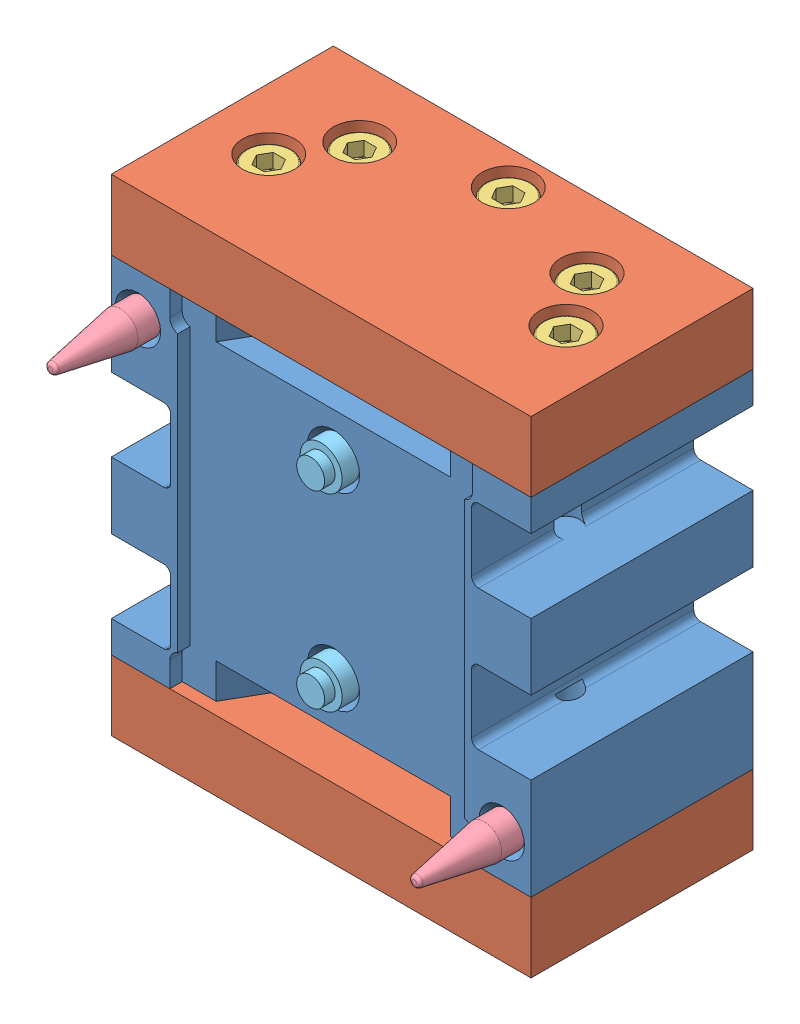
SolidWorks assembly Матрица в сборе, configuration По умолчанию. Lengths in mm.
Overall size (120 139 88.5).
17 component instances, 5 part files, 34 mates.
Components (placement in the parent):
- Матрица-1: Матрица [По умолчанию] at origin size (120 99 63.5)
- Боковина пресс-формы-1: Боковина пресс-формы [По умолчанию] at (0 -49.5 31.75) x (1 0 0) z (0 -1 0) size (120 63.5 20)
- socket head cap screw_iso-1: socket head cap screw_iso [ISO 4762 M8 x 16 - 16N] at (-42.5 -67.5 36) x (0 1 0) z (0 0 1) size (24 13 13)
- socket head cap screw_iso-2: socket head cap screw_iso [ISO 4762 M8 x 16 - 16N] at (-32.5 -67.5 20) x (0 1 0) z (0 0 1) size (24 13 13)
- socket head cap screw_iso-3: socket head cap screw_iso [ISO 4762 M8 x 16 - 16N] at (0 -67.5 10) x (0 1 0) z (0 0 1) size (24 13 13)
- socket head cap screw_iso-4: socket head cap screw_iso [ISO 4762 M8 x 16 - 16N] at (32.5 -67.5 20) x (0 1 0) z (0 0 1) size (24 13 13)
- socket head cap screw_iso-5: socket head cap screw_iso [ISO 4762 M8 x 16 - 16N] at (42.5 -67.5 36) x (0 1 0) z (0 0 1) size (24 13 13)
- socket head cap screw_iso-11: socket head cap screw_iso [ISO 4762 M8 x 16 - 16N] at (-42.5 67.5 36) x (0 -1 0) z (0 0 1) size (24 13 13)
- socket head cap screw_iso-12: socket head cap screw_iso [ISO 4762 M8 x 16 - 16N] at (-32.5 67.5 20) x (0 -1 0) z (0 0 1) size (24 13 13)
- socket head cap screw_iso-13: socket head cap screw_iso [ISO 4762 M8 x 16 - 16N] at (0 67.5 10) x (0 -1 0) z (0 0 1) size (24 13 13)
- socket head cap screw_iso-14: socket head cap screw_iso [ISO 4762 M8 x 16 - 16N] at (32.5 67.5 20) x (0 -1 0) z (0 0 1) size (24 13 13)
- socket head cap screw_iso-15: socket head cap screw_iso [ISO 4762 M8 x 16 - 16N] at (42.5 67.5 36) x (0 -1 0) z (0 0 1) size (24 13 13)
- Боковина пресс-формы-3: Боковина пресс-формы [По умолчанию] at (0 49.5 31.75) x (-1 0 0) z (0 1 0) size (120 63.5 20)
- КОнус-1: КОнус [По умолчанию] at (-52.375 37.5 33.5) x (0 0 1) z (-0.953769 -0.300541 0) size (55 10 10)
- КОнус-2: КОнус [По умолчанию] at (51.625 -37.5 33.5) x (0 0 1) z (-0.599492 0.800381 0) size (55 10 10)
- ВТулка-1: ВТулка [По умолчанию] at (0 27 30) x (0 0 1) z (-0.845392 0.534146 0) size (36.5 12 12)
- ВТулка-2: ВТулка [По умолчанию] at (0 -27 30) x (0 0 1) z (-0.844306 0.535861 0) size (36.5 12 12)
Mates (geometry in assembly coordinates):
- Совпадение1: coincident anti-aligned: plane of Матрица-1 through (-60 -49.5 63.5) normal (0 -1 0); plane of Боковина пресс-формы-1 through (0 -49.5 31.75) normal (0 1 0)
- Концентричный1: concentric aligned: cylinder of Матрица-1 through (42.5 -19.5 36) axis (0 -1 0) radius 4; cylinder of Боковина пресс-формы-1 through (42.5 -49.5 36) axis (0 -1 0) radius 4
- Концентричный2: concentric aligned: cylinder of Матрица-1 through (-42.5 -19.5 36) axis (0 -1 0) radius 4; cylinder of Боковина пресс-формы-1 through (-42.5 -49.5 36) axis (0 -1 0) radius 4
- Концентричный3: concentric aligned: cylinder of Боковина пресс-формы-1 through (-42.5 -49.5 36) axis (0 -1 0) radius 4; cylinder of socket head cap screw_iso-1 through (-42.5 -99.25 36) axis (0 -1 0) radius 6.5
- Совпадение2: coincident anti-aligned: plane of Боковина пресс-формы-1 through (-42.5 -59.5 36) normal (0 -1 0); plane of socket head cap screw_iso-1 through (-49 -59.5 36) normal (0 1 0)
- Концентричный4: concentric aligned: cylinder of Боковина пресс-формы-1 through (-32.5 -49.5 20) axis (0 -1 0) radius 4; cylinder of socket head cap screw_iso-2 through (-32.5 -99.25 20) axis (0 -1 0) radius 6.5
- Совпадение3: coincident anti-aligned: plane of Боковина пресс-формы-1 through (-32.5 -59.5 20) normal (0 -1 0); plane of socket head cap screw_iso-2 through (-39 -59.5 20) normal (0 1 0)
- Концентричный5: concentric aligned: cylinder of Боковина пресс-формы-1 through (0 -59.5 10) axis (0 -1 0) radius 7.5; cylinder of socket head cap screw_iso-3 through (0 -99.25 10) axis (0 -1 0) radius 6.5
- Совпадение4: coincident anti-aligned: plane of Боковина пресс-формы-1 through (0 -59.5 10) normal (0 -1 0); plane of socket head cap screw_iso-3 through (-6.5 -59.5 10) normal (0 1 0)
- Концентричный6: concentric aligned: cylinder of Боковина пресс-формы-1 through (32.5 -59.5 20) axis (0 -1 0) radius 7.5; cylinder of socket head cap screw_iso-4 through (32.5 -99.25 20) axis (0 -1 0) radius 6.5
- Совпадение5: coincident anti-aligned: plane of Боковина пресс-формы-1 through (32.5 -59.5 20) normal (0 -1 0); plane of socket head cap screw_iso-4 through (26 -59.5 20) normal (0 1 0)
- Концентричный7: concentric aligned: cylinder of Боковина пресс-формы-1 through (42.5 -59.5 36) axis (0 -1 0) radius 7.5; cylinder of socket head cap screw_iso-5 through (42.5 -99.25 36) axis (0 -1 0) radius 6.5
- Совпадение6: coincident anti-aligned: plane of Боковина пресс-формы-1 through (42.5 -59.5 36) normal (0 -1 0); plane of socket head cap screw_iso-5 through (36 -59.5 36) normal (0 1 0)
- Совпадение7: coincident anti-aligned: plane of Матрица-1 through (-60 49.5 63.5) normal (0 1 0); plane of Боковина пресс-формы-3 through (0 49.5 31.75) normal (0 -1 0)
- Концентричный8: concentric aligned: cylinder of Матрица-1 through (-42.5 19.5 36) axis (0 1 0) radius 4; cylinder of Боковина пресс-формы-3 through (-42.5 49.5 36) axis (0 1 0) radius 4
- Концентричный9: concentric aligned: cylinder of Матрица-1 through (42.5 19.5 36) axis (0 1 0) radius 4; cylinder of Боковина пресс-формы-3 through (42.5 49.5 36) axis (0 1 0) radius 4
- Концентричный10: concentric aligned: cylinder of Боковина пресс-формы-3 through (-42.5 59.5 36) axis (0 1 0) radius 7.5; cylinder of socket head cap screw_iso-11 through (-42.5 99.25 36) axis (0 1 0) radius 6.5
- Совпадение8: coincident anti-aligned: plane of Боковина пресс-формы-3 through (-42.5 59.5 36) normal (0 1 0); plane of socket head cap screw_iso-11 through (-36 59.5 36) normal (0 -1 0)
- Концентричный11: concentric aligned: cylinder of Боковина пресс-формы-3 through (-32.5 49.5 20) axis (0 1 0) radius 4; cylinder of socket head cap screw_iso-12 through (-32.5 99.25 20) axis (0 1 0) radius 6.5
- Совпадение9: coincident anti-aligned: plane of Боковина пресс-формы-3 through (-32.5 59.5 20) normal (0 1 0); plane of socket head cap screw_iso-12 through (-26 59.5 20) normal (0 -1 0)
- Концентричный12: concentric aligned: cylinder of Боковина пресс-формы-3 through (0 49.5 10) axis (0 1 0) radius 4; cylinder of socket head cap screw_iso-13 through (0 99.25 10) axis (0 1 0) radius 6.5
- Совпадение10: coincident anti-aligned: plane of Боковина пресс-формы-3 through (0 59.5 10) normal (0 1 0); plane of socket head cap screw_iso-13 through (6.5 59.5 10) normal (0 -1 0)
- Концентричный13: concentric aligned: cylinder of Боковина пресс-формы-3 through (32.5 49.5 20) axis (0 1 0) radius 4; cylinder of socket head cap screw_iso-14 through (32.5 99.25 20) axis (0 1 0) radius 6.5
- Совпадение11: coincident anti-aligned: plane of Боковина пресс-формы-3 through (32.5 59.5 20) normal (0 1 0); plane of socket head cap screw_iso-14 through (39 59.5 20) normal (0 -1 0)
- Концентричный14: concentric aligned: cylinder of Боковина пресс-формы-3 through (42.5 49.5 36) axis (0 1 0) radius 4; cylinder of socket head cap screw_iso-15 through (42.5 99.25 36) axis (0 1 0) radius 6.5
- Совпадение12: coincident anti-aligned: plane of Боковина пресс-формы-3 through (42.5 59.5 36) normal (0 1 0); plane of socket head cap screw_iso-15 through (49 59.5 36) normal (0 -1 0)
- Концентричный15: concentric anti-aligned: cylinder of Матрица-1 through (-52.375 37.5 33.5) axis (0 0 1) radius 5; cylinder of КОнус-1 through (-52.375 37.5 33.5) axis (0 0 -1) radius 5
- Совпадение13: coincident anti-aligned: plane of Матрица-1 through (-52.375 37.5 33.5) normal (0 0 1); plane of КОнус-1 through (-52.375 37.5 33.5) normal (0 0 -1)
- Концентричный16: concentric anti-aligned: cylinder of Матрица-1 through (51.625 -37.5 33.5) axis (0 0 1) radius 5; cylinder of КОнус-2 through (51.625 -37.5 33.5) axis (0 0 -1) radius 5
- Совпадение14: coincident anti-aligned: plane of Матрица-1 through (51.625 -37.5 33.5) normal (0 0 1); plane of КОнус-2 through (51.625 -37.5 33.5) normal (0 0 -1)
- Концентричный18: concentric aligned: cylinder of Матрица-1 through (0 27 30) axis (0 0 1) radius 6; cylinder of ВТулка-1 through (0 27 66.5) axis (0 0 1) radius 6
- Совпадение15: coincident anti-aligned: plane of Матрица-1 through (0 27 30) normal (0 0 1); plane of ВТулка-1 through (0 27 30) normal (0 0 -1)
- Концентричный19: concentric aligned: cylinder of Матрица-1 through (0 -27 30) axis (0 0 1) radius 6; cylinder of ВТулка-2 through (0 -27 66.5) axis (0 0 1) radius 6
- Совпадение16: coincident anti-aligned: plane of Матрица-1 through (0 -27 30) normal (0 0 1); plane of ВТулка-2 through (0 -27 30) normal (0 0 -1)
